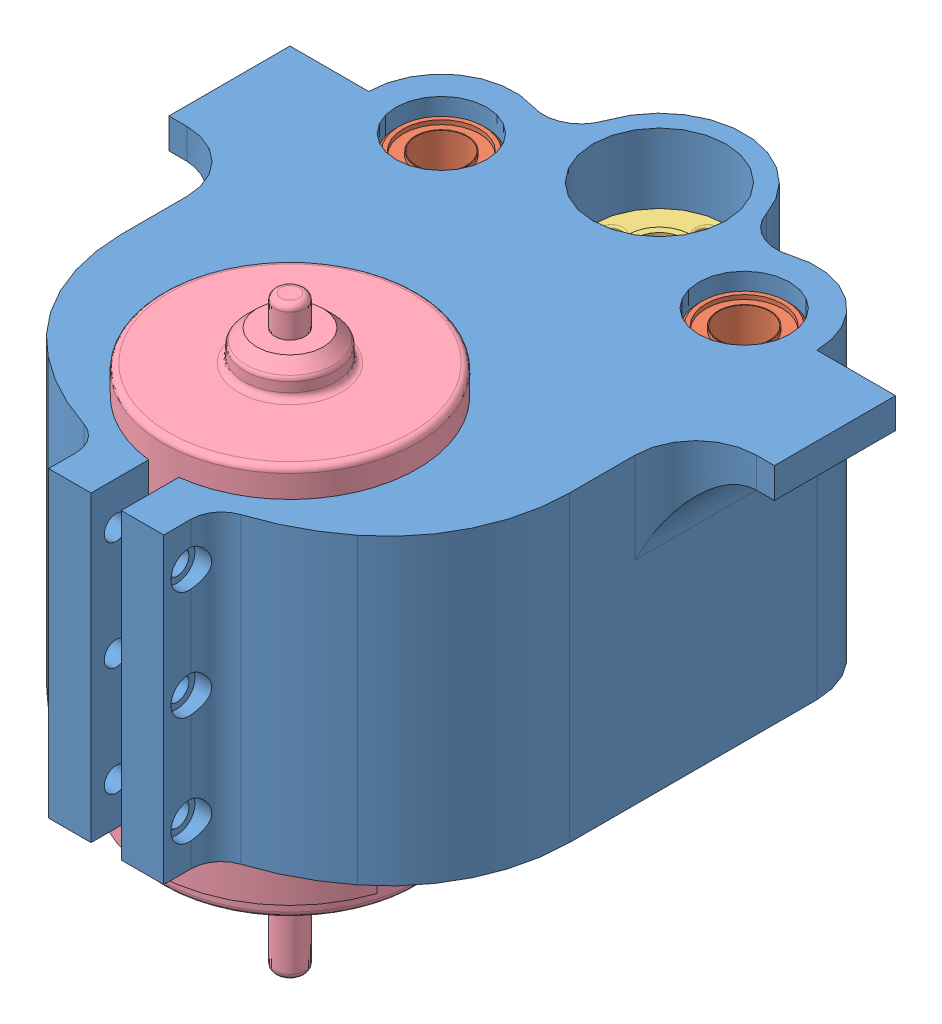
SolidWorks assembly New Z Assem, configuration Default. Lengths in mm.
Overall size (100 96.7 105.35).
5 component instances, 4 part files, 7 mates.
Components (placement in the parent):
- New Z-1: New Z [Default] at (8.9587 19.7661 58.9622) size (100 50 105.35)
- LM8LUU Long Type Linear Bearing-1: LM8LUU Long Type Linear Bearing [Default] at (-16.0413 67.2661 58.9622) x (0 -1 0) z (0 0 1) size (45 15 15)
- LM8LUU Long Type Linear Bearing-2: LM8LUU Long Type Linear Bearing [Default] at (33.9587 67.2661 58.9622) x (0 -1 0) z (0 0 1) size (45 15 15)
- LeadScrew Nut 8mm x 2mmPitch-1: LeadScrew Nut 8mm x 2mmPitch [Default] at (8.9587 58.2661 47.9622) x (1 0 0) z (0 1 0) size (22 22 16.05)
- High Speed 775 Motor Low Noise DC 12V-24V Large Torque Motor Ball Bearing Tools-1: High Speed 775 Motor Low Noise DC 12V-24V Large Torque Motor Ball Bearing Tools [Default] at (8.9587 74.4661 108.9622) x (0 -1 0) z (0 0 1) size (96.7 43.88 45)
Mates (geometry in assembly coordinates):
- Concentric1: concentric: cylinder of assembly; cylinder of assembly; cylinder of New Z-1 through (-16.0413 69.7661 58.9622) axis (0 -1 0) radius 7.5; cylinder of LM8LUU Long Type Linear Bearing-1 through (-16.0413 67.2661 58.9622) axis (0 1 0) radius 7.5
- Distance1: distance = 2.5 mm: plane of assembly; plane of assembly; plane of New Z-1 through (8.9587 69.7661 58.9622) normal (0 1 0); plane of LM8LUU Long Type Linear Bearing-1 through (-8.5413 67.2661 58.9622) normal (0 1 0)
- Concentric2: concentric: cylinder of assembly; cylinder of assembly; cylinder of New Z-1 through (8.9587 69.7661 47.9622) axis (0 -1 0) radius 5.1; cylinder of LeadScrew Nut 8mm x 2mmPitch-1 through (8.9587 44.7661 47.9622) axis (0 1 0) radius 5.1
- Coincident2: coincident: plane of assembly; circle of assembly; plane of New Z-1 through (8.9587 54.7661 47.9622) normal (0 1 0); circle of LeadScrew Nut 8mm x 2mmPitch-1
- Concentric3: concentric: cylinder of assembly; cylinder of assembly; cylinder of New Z-1 through (8.9587 19.7651 55.9622) axis (0 1 0) radius 1.5; cylinder of LeadScrew Nut 8mm x 2mmPitch-1 through (8.9587 54.7661 55.9622) axis (0 1 0) radius 1.75
- Concentric4: concentric: cylinder of assembly; cylinder of assembly; cylinder of New Z-1 through (8.9587 69.7661 108.9622) axis (0 -1 0) radius 20.5; cylinder of High Speed 775 Motor Low Noise DC 12V-24V Large Torque Motor Ball Bearing Tools-1 through (8.9587 47.7661 108.9622) axis (0 1 0) radius 21
- Distance2: distance = 10 mm: plane of assembly; plane of assembly; plane of High Speed 775 Motor Low Noise DC 12V-24V Large Torque Motor Ball Bearing Tools-1 through (8.9587 9.7661 108.9622) normal (0 -1 0); plane of New Z-1 through (8.9587 19.7661 58.9622) normal (0 -1 0)
